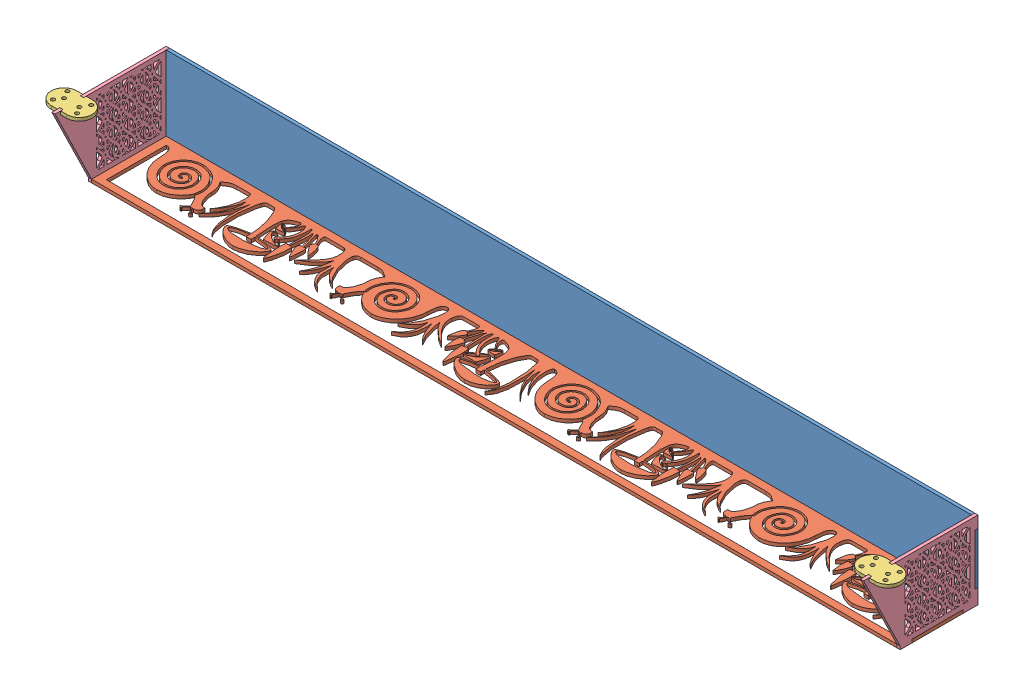
SolidWorks assembly Spicerack_bevel_whole, configuration Default. Lengths in mm.
Overall size (831.17 76.23 111.89).
9 component instances, 4 part files, 6 mates.
Components (placement in the parent):
- Spicerack-1: Spicerack [Default] at (-0.8868 -50.6717 -137.2518) size (794.35 76.23 76.17)
  - Spicerack_bottom-1: Spicerack_bottom [Default] at (66.3776 576.7906 620.9352) size (794.35 76.17 3.17)
  - Spicerack_front-1: Spicerack_front [Default] at (314.1576 526.369 508.4836) x (1 0 0) z (0 -1 0) size (794.35 76.18 3.28)
- Spicerack_bevel-1: Spicerack_bevel [Default] at (730.7478 573.7758 558.2742) x (1 0 0) z (0 -1 0) size (40 111.89 76.17)
  - Spicerack_mount_bevel-1: Spicerack_mount_bevel [Default] at (23.9298 22.164 25.0786) size (40 25 3.17)
  - Spicerack_side_bevel-1: Spicerack_side_bevel [Default] at (5.9681 -22.8444 67.6943) x (0 0 1) z (-1 0 0) size (76.17 111.89 3.17)
- Spicerack_bevel-2: Spicerack_bevel [Default] at (-60.4272 573.7758 558.2742) x (1 0 0) z (0 -1 0) size (40 111.89 76.17)
  - Spicerack_mount_bevel-1: Spicerack_mount_bevel [Default] at (23.9298 22.164 25.0786) size (40 25 3.17)
  - Spicerack_side_bevel-1: Spicerack_side_bevel [Default] at (5.9681 -22.8444 67.6943) x (0 0 1) z (-1 0 0) size (76.17 111.89 3.17)
Mates (geometry in assembly coordinates):
- Coincident1: coincident: plane of Spicerack-1/Spicerack_bottom-1 through (65.4908 526.1189 486.8584) normal (0 0 1); plane of Spicerack_bevel-1/Spicerack_side_bevel-1 through (733.5409 487.1973 486.8584) normal (0 0 -1)
- Coincident2: coincident: plane of Spicerack-1/Spicerack_front-1 through (313.2707 475.6973 371.2318) normal (0 1 0); plane of Spicerack_bevel-1/Spicerack_side_bevel-1 through (733.5409 475.6973 548.3584) normal (0 -1 0)
- Coincident3: coincident: plane of Spicerack-1/Spicerack_bottom-1 through (733.5409 548.6973 486.8584) normal (1 0 0); plane of Spicerack_bevel-1/Spicerack_side_bevel-1 through (733.5409 506.0815 535.4298) normal (-1 0 0)
- Coincident4: coincident: plane of Spicerack-1/Spicerack_bottom-1 through (65.4908 526.1189 486.8584) normal (0 0 1); plane of Spicerack_bevel-2/Spicerack_side_bevel-1 through (-57.6341 487.1973 486.8584) normal (0 0 -1)
- Coincident5: coincident: plane of Spicerack-1/Spicerack_front-1 through (313.2707 475.6973 371.2318) normal (0 1 0); plane of Spicerack_bevel-2/Spicerack_side_bevel-1 through (-57.6341 475.6973 548.3584) normal (0 -1 0)
- Coincident6: coincident: plane of Spicerack-1/Spicerack_front-1 through (-54.4591 472.5223 486.8584) normal (-1 0 0); plane of Spicerack_bevel-2/Spicerack_side_bevel-1 through (-54.4591 506.0815 535.4298) normal (1 0 0)
